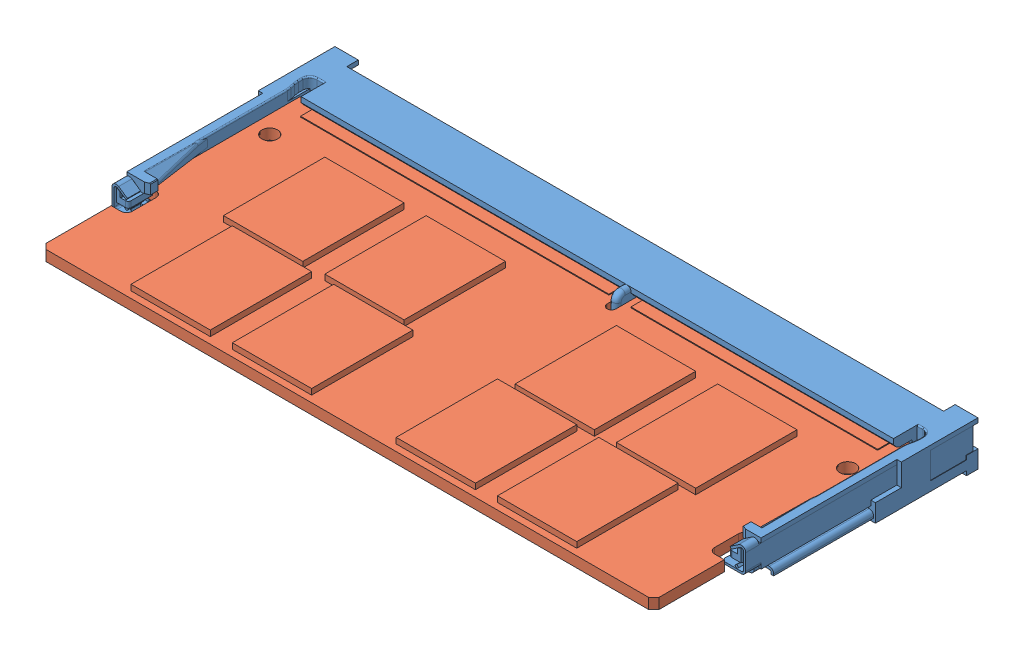
SolidWorks assembly Assembly, configuration Default. Lengths in mm.
Overall size (73 5.55 35.1).
2 component instances, 2 part files, 6 mates.
Components (placement in the parent):
- 2309410-2-1: 2309410-2 [Default] at (0 3.025 20.82) size (73 5.55 25.85)
- DDR4 Board-1: DDR4 Board [Default] at (0 4.0499 15.0691) x (1 0 0) z (0 -1 0) size (69.6 30 2.5)
Mates (geometry in assembly coordinates):
- Coincident1: coincident: plane of 2309410-2-1 through (0 3.025 20.82) normal (1 0 0); plane of assembly
- Coincident2: coincident: plane of 2309410-2-1 through (-33.38 0 13.47) normal (0 -1 0); plane of assembly
- Coincident3: coincident: plane of 2309410-2-1 through (0 3.025 0) normal (0 0 1); plane of assembly
- Width1: width: plane of DDR4 Board-1 through (-34.8 2.8499 -1.1201) normal (-1 0 0); plane of DDR4 Board-1 through (34.8 2.8499 -1.1201) normal (1 0 0); plane of 2309410-2-1 through (-34.95 0.75 19.1) normal (1 0 0); plane of 2309410-2-1 through (34.95 0.75 3.87) normal (-1 0 0)
- Width2: width: plane of DDR4 Board-1 through (0 2.8499 13.2799) normal (0 -1 0); plane of DDR4 Board-1 through (0 4.0499 13.2799) normal (0 1 0); plane of 2309410-2-1 through (0 2.77 20.82) normal (0 1 0); plane of 2309410-2-1 through (-34.95 4.1299 -0.28) normal (0 -1 0)
- Coincident4: coincident: plane of 2309410-2-1 through (0 0.75 18.0691) normal (0 0 -1); plane of DDR4 Board-1 through (36.55 4.0499 18.0691) normal (0 0 1)
